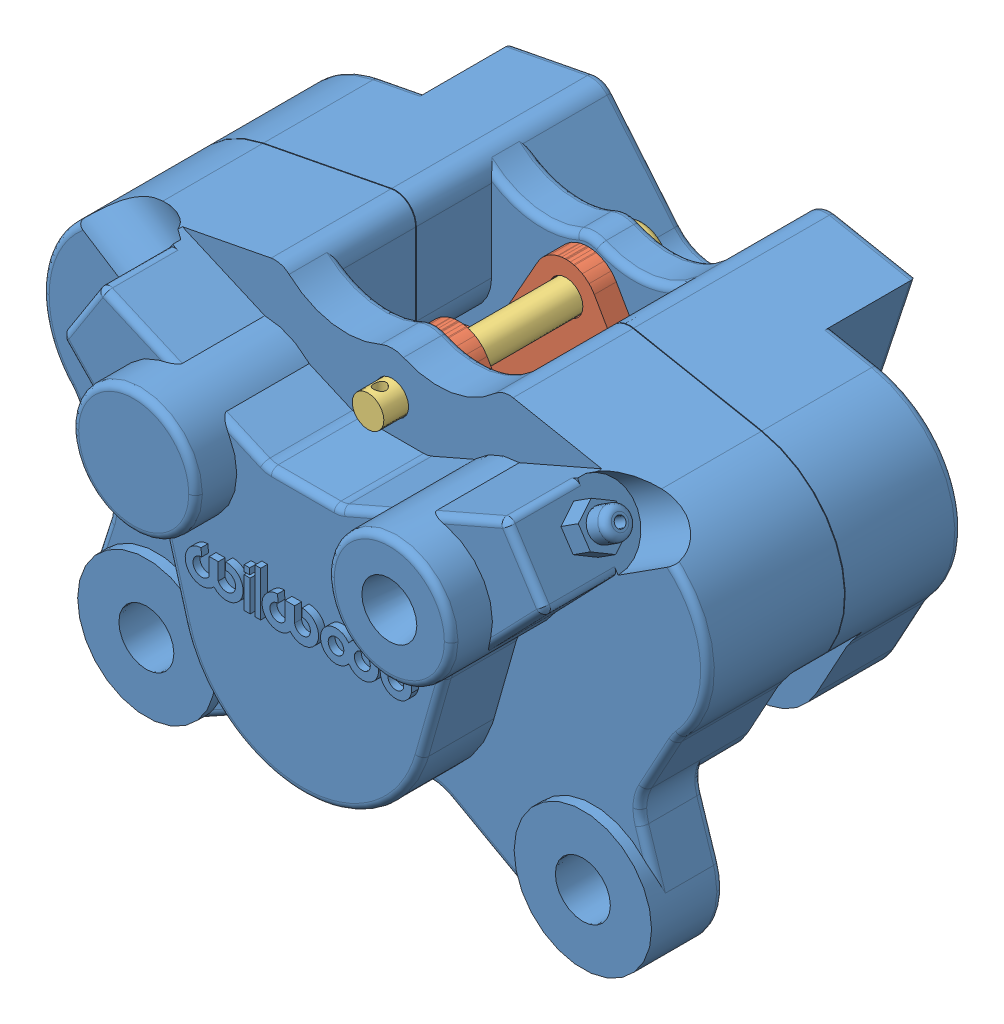
SolidWorks assembly Brake Caliper, configuration Default. Lengths in mm.
Overall size (101.75 67.09 67.01).
4 component instances, 3 part files, 9 mates.
Components (placement in the parent):
- Brake Caliper Frame-1: Brake Caliper Frame [Default] at origin size (101.75 67.09 67.01)
- Brake pad-1: Brake pad [Default] at (-23.5554 37.6919 -13.7004) x (0.999992 0.003877 0) z (0 0 1) size (67.93 44.48 7.61)
- Brake pad-2: Brake pad [Default] at (-23.5554 37.6919 -29.2996) x (-0.999992 -0.003877 0) z (0 0 -1) size (67.93 44.48 7.61)
- Brake Pin-1: Brake Pin [Default] at (-23.5554 37.6919 -26.0423) x (0 0 1) z (0.999547 0.030097 0) size (39.8 8.85 8.85)
Mates (geometry in assembly coordinates):
- Coincident1: coincident anti-aligned: plane of Brake Caliper Frame-1 through (0 0 -10.5) normal (0 0 -1); plane of Brake pad-1 through (-23.5554 37.6919 -10.5) normal (0 0 1)
- Coincident2: coincident anti-aligned: plane of Brake Caliper Frame-1 through (0 0 -32.5) normal (0 0 1); plane of Brake pad-2 through (-23.5554 37.6919 -32.5) normal (0 0 -1)
- Concentric1: concentric aligned: cylinder of Brake Caliper Frame-1 through (-23.5554 37.6919 -38.5) axis (0 0 1) radius 2.4; cylinder of Brake pad-2 through (-23.5554 37.6919 -32.5) axis (0 0 1) radius 2.45
- Concentric2: concentric aligned: cylinder of Brake Caliper Frame-1 through (-23.5554 37.6919 -4) axis (0 0 -1) radius 2.4; cylinder of Brake pad-1 through (-23.5554 37.6919 -10.5) axis (0 0 -1) radius 2.45
- Concentric3: concentric aligned: cylinder of Brake pad-1 through (-23.5554 37.6919 -10.5) axis (0 0 -1) radius 2.45; cylinder of ? through (-23.5554 37.6919 -38.5) axis (0 0 -1) radius 2.3
- Coincident3: coincident anti-aligned: plane of Brake Caliper Frame-1 through (0 0 -38.5) normal (0 0 -1); plane of ? through (-23.4861 35.3929 -38.5) normal (0 0 1)
- Coincident4: coordinate: point of Brake Caliper Frame-1; point of assembly
- Parallel1: parallel anti-aligned: plane of Brake Caliper Frame-1 through (-47.371 -15.5951 0) normal (0.949851 0.312702 0); plane of Brake pad-2 through (-60.8096 25.4274 -32.5) normal (-0.949851 -0.312702 0)
- Parallel2: parallel anti-aligned: plane of Brake Caliper Frame-1 through (-47.371 -15.5951 0) normal (0.949851 0.312702 0); plane of Brake pad-1 through (-55.283 15.036 -18.0997) normal (-0.949851 -0.312702 0)
